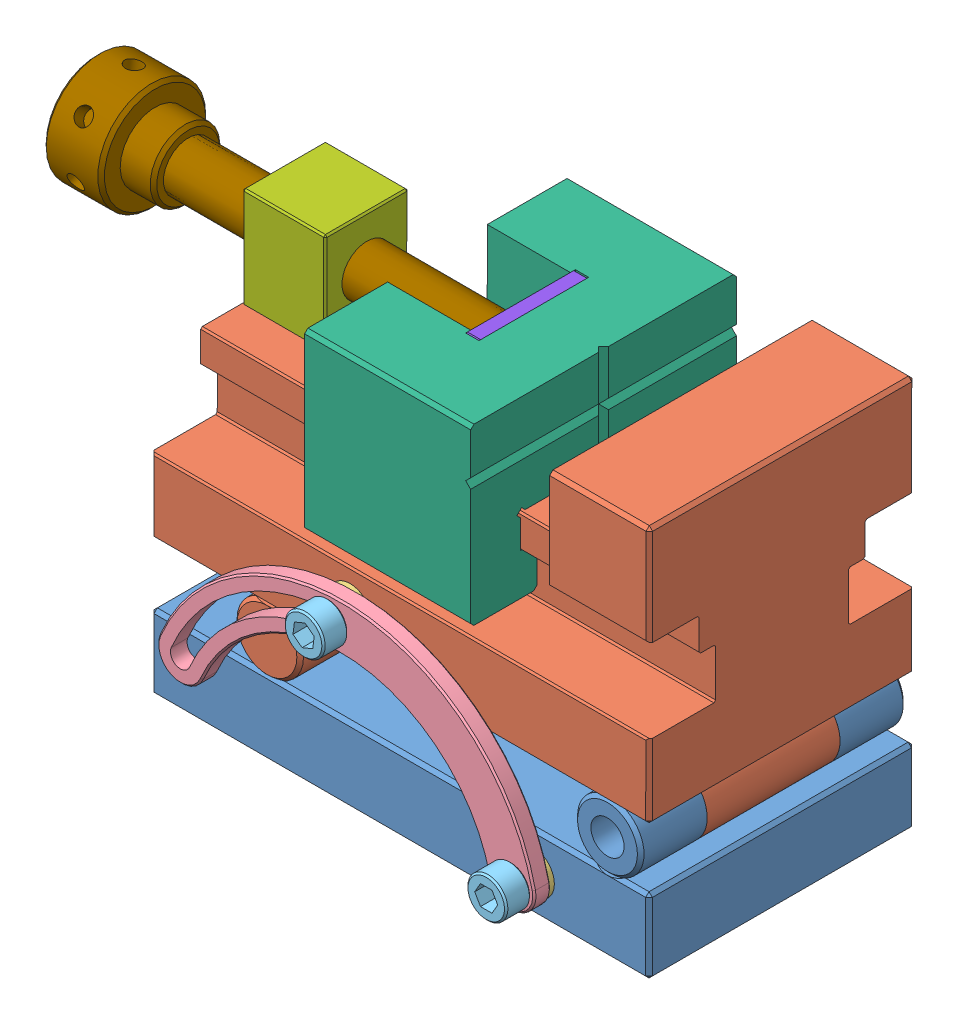
SolidWorks assembly Lab12_task1, configuration Default. Lengths in mm.
Overall size (412.61 252.06 188).
11 component instances, 9 part files, 23 mates.
Components (placement in the parent):
- Base-1: Base [Default] at origin size (300 83 160)
- Fixed jaw-1: Fixed jaw [Default] at (0.0189 80.9738 0) x (0.999999 -0.001048 0) z (0 0 1) size (300 193 160)
- Washer-1: Washer [Default] at (-70 22.5 83) x (0.817485 0.57595 0) z (-0.57595 0.817485 0) size (26 3 26)
- Washer-2: Washer [Default] at (-179.9564 104.6625 83) x (0.601137 0.799146 0) z (-0.799146 0.601137 0) size (26 3 26)
- Slotted link-1: Slotted link [Default] at (-70 22.5 83) x (0.995665 -0.093012 0) z (-0.093012 -0.995665 0) size (228 10 100.98)
- Allen bolt-1: Allen bolt [Default] at (-70 22.5 93) x (0 0 -1) z (1 0 0) size (61 24 24)
- Allen bolt-2: Allen bolt [Default] at (-179.9564 104.6625 93) x (0 0 -1) z (0.923728 0.383049 0) size (61 24 24)
- Sliding jaw-2: Sliding jaw [Default] at (-207.4611 131.1913 0) x (0.999999 -0.001048 0) z (0 0 1) size (100 105 160)
- Screw fastening-1: Screw fastening [Default] at (-274.8814 176.262 0) x (0.999999 -0.001048 0) z (0 0 1) size (50 110 50)
- Retaining plate-1: Retaining plate [Default] at (-153.414 176.1347 0) x (0.999999 -0.001048 0) z (0 0 1) size (8 60 66)
- Screw-1: Screw [Default] at (-357.3824 206.3485 0) x (0.999999 -0.001048 0) z (-0.000823 -0.784611 0.619987) size (263 65 65)
Mates (geometry in assembly coordinates):
- Concentric1: concentric: cylinder of Base-1 through (-25 63 -80) axis (0 0 1) radius 20; cylinder of Fixed jaw-1 through (-25 63 40) axis (0 0 -1) radius 20
- Coincident1: coincident: plane of Base-1 through (-45 500000 40) normal (0 0 -1); plane of Fixed jaw-1 through (-25 63 40) normal (0 0 1)
- Concentric2: concentric: cylinder of Base-1 through (-70 22.5 80) axis (0 0 1) radius 5.1; circle of Washer-1
- Concentric3: concentric: cylinder of Fixed jaw-1 through (-179.9564 104.6625 80) axis (0 0 1) radius 5.1; circle of Washer-2
- Concentric4: concentric: circle of Base-1; cylinder of Allen bolt-1 through (-70 22.5 47) axis (0 0 1) radius 6
- Concentric7: concentric: cylinder of Fixed jaw-1 through (-179.9564 104.6625 80) axis (0 0 1) radius 5.1; cylinder of Allen bolt-2 through (-179.9564 104.6625 47) axis (0 0 1) radius 6
- Tangent2: tangent: cylinder of Slotted link-1 through (-172.5443 -0.0756 83) axis (0 0 1) radius 99; cylinder of Allen bolt-2 through (-179.9564 104.6625 47) axis (0 0 1) radius 6
- Coincident9: coincident: plane of Fixed jaw-1 through (-299.8185 236.2882 80) normal (0 0 1); plane of Washer-2 through (-179.9564 104.6625 80) normal (0 0 -1)
- Coincident12: coincident: plane of Slotted link-1 through (-121.2722 11.2122 93) normal (0 0 1); plane of Allen bolt-2 through (-179.9564 104.6625 93) normal (0 0 -1)
- Coincident16: coincident: plane of Fixed jaw-1 through (-299.8824 176.2882 50) normal (0.001048 0.999999 0); plane of Sliding jaw-2 through (-207.414 176.1913 50) normal (-0.001048 -0.999999 0)
- Coincident17: coincident: plane of Fixed jaw-1 through (-299.9348 126.2883 40) normal (0 0 1); plane of Sliding jaw-2 through (-207.414 176.1913 40) normal (0 0 -1)
- Coincident19: coincident: plane of Base-1 through (-300 45 80) normal (0 0 1); plane of Washer-1 through (-70 22.5 80) normal (0 0 -1)
- Coincident20: coincident: plane of Washer-1 through (-70 22.5 83) normal (0 0 1); plane of Slotted link-1 through (-121.2722 11.2122 83) normal (0 0 -1)
- Coincident21: coincident: plane of Slotted link-1 through (-121.2722 11.2122 93) normal (0 0 1); plane of Allen bolt-1 through (-70 22.5 93) normal (0 0 -1)
- Concentric9: concentric: cylinder of Slotted link-1 through (-70 22.5 83) axis (0 0 1) radius 6; cylinder of Allen bolt-1 through (-70 22.5 47) axis (0 0 1) radius 6
- Coincident22: coincident: plane of Fixed jaw-1 through (-259.9783 83.8199 15) normal (-0.999999 0.001048 0); plane of Screw fastening-1 through (-259.9338 126.2463 -15) normal (0.999999 -0.001048 0)
- Coincident23: coincident: plane of Fixed jaw-1 through (-289.9783 83.8514 15) normal (0 0 -1); plane of Screw fastening-1 through (-259.9338 126.2463 15) normal (0 0 1)
- Coincident24: coincident: plane of Fixed jaw-1 through (-299.8824 176.2882 50) normal (0.001048 0.999999 0); plane of Screw fastening-1 through (-274.8814 176.262 0) normal (-0.001048 -0.999999 0)
- Coincident25: coincident: plane of Sliding jaw-2 through (-149.4612 131.1295 -30) normal (-0.999999 0.001048 0); plane of Retaining plate-1 through (-149.3511 236.1305 -33) normal (0.999999 -0.001048 0)
- Coincident26: coincident: plane of Sliding jaw-2 through (-157.4612 131.1379 33) normal (0 0 -1); plane of Retaining plate-1 through (-149.3511 236.1305 33) normal (0 0 1)
- Coincident27: coincident: plane of Fixed jaw-1 through (-299.8824 176.2882 50) normal (0.001048 0.999999 0); plane of Retaining plate-1 through (-153.414 176.1347 0) normal (-0.001048 -0.999999 0)
- Screw1: screw = 3: cylinder of Screw fastening-1 through (-299.8509 206.2882 0) axis (0.999999 -0.001048 0) radius 12; cylinder of Screw-1 through (-157.3826 206.1389 0) axis (-0.999999 0.001048 0) radius 15
- Coincident28: coincident: plane of Retaining plate-1 through (-157.3511 236.1388 -33) normal (-0.999999 0.001048 0); plane of Screw-1 through (-157.3826 206.1389 0) normal (0.999999 -0.001048 0)
